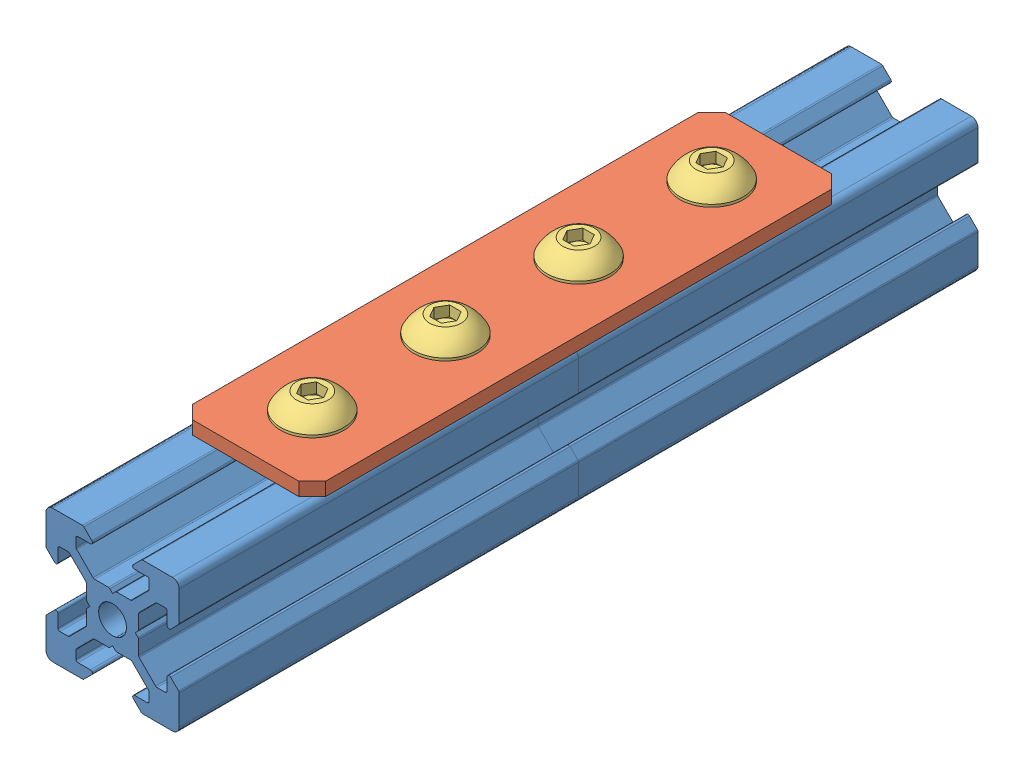
SolidWorks assembly П-Пластина 20 серия 1х4 4отв 20х80х2 СБ, configuration По умолчанию. Lengths in mm.
Overall size (20 24.75 120).
7 component instances, 3 part files, 14 mates.
Components (placement in the parent):
- 2020100-1: 2020100 [По умолчанию] at origin size (20 20 60)
- 2020100-2: 2020100 [По умолчанию] at (0 0 -60) size (20 20 60)
- П-Пластина 20 серия 1х4 4отв 20х80х2-1: П-Пластина 20 серия 1х4 4отв 20х80х2 [По умолчанию] at (0 12 0) x (1 0 0) z (0 -1 0) size (20 80 2)
- socket button head screw_iso-1: socket button head screw_iso [ISO 7380 - M5 x 10 - 10N] at (0 14.75 10) x (0 -1 0) z (0 0 1) size (12.75 9.5 9.5)
- socket button head screw_iso-2: socket button head screw_iso [ISO 7380 - M5 x 10 - 10N] at (0 14.75 -10) x (0 -1 0) z (0 0 1) size (12.75 9.5 9.5)
- socket button head screw_iso-3: socket button head screw_iso [ISO 7380 - M5 x 10 - 10N] at (0 14.75 -30) x (0 -1 0) z (0 0 1) size (12.75 9.5 9.5)
- socket button head screw_iso-4: socket button head screw_iso [ISO 7380 - M5 x 10 - 10N] at (0 14.75 30) x (0 -1 0) z (0 0 1) size (12.75 9.5 9.5)
Mates (geometry in assembly coordinates):
- Совпадение1: coincident anti-aligned: plane of 2020100-1 through (0 0 0) normal (0 0 -1); plane of 2020100-2 through (0 0 0) normal (0 0 1)
- Совпадение2: coincident aligned: plane of 2020100-1 through (-10 10 60) normal (0 1 0); plane of 2020100-2 through (-10 10 0) normal (0 1 0)
- Совпадение3: coincident aligned: plane of 2020100-1 through (10 10 60) normal (1 0 0); plane of 2020100-2 through (10 10 0) normal (1 0 0)
- Совпадение4: coincident anti-aligned: plane of 2020100-1 through (-10 10 60) normal (0 1 0); plane of П-Пластина 20 серия 1х4 4отв 20х80х2-1 through (0 10 0) normal (0 -1 0)
- Совпадение5: coincident aligned: plane of 2020100-1 through (10 10 60) normal (1 0 0); plane of П-Пластина 20 серия 1х4 4отв 20х80х2-1 through (10 10 -40) normal (1 0 0)
- Расстояние1: distance = 20 mm aligned: plane of П-Пластина 20 серия 1х4 4отв 20х80х2-1 through (-10 10 40) normal (0 0 1); plane of 2020100-1 through (0 0 60) normal (0 0 1)
- Концентричный1: concentric anti-aligned: cylinder of П-Пластина 20 серия 1х4 4отв 20х80х2-1 through (0 10 10) axis (0 -1 0) radius 2.75; cylinder of socket button head screw_iso-1 through (0 14.75 10) axis (0 1 0) radius 4.75
- Совпадение7: coincident anti-aligned: plane of П-Пластина 20 серия 1х4 4отв 20х80х2-1 through (0 12 0) normal (0 1 0); plane of socket button head screw_iso-1 through (2.5 12 10) normal (0 -1 0)
- Концентричный2: concentric anti-aligned: cylinder of П-Пластина 20 серия 1х4 4отв 20х80х2-1 through (0 10 -10) axis (0 -1 0) radius 2.75; cylinder of socket button head screw_iso-2 through (0 14.75 -10) axis (0 1 0) radius 4.75
- Совпадение8: coincident anti-aligned: plane of П-Пластина 20 серия 1х4 4отв 20х80х2-1 through (0 12 0) normal (0 1 0); plane of socket button head screw_iso-2 through (2.5 12 -10) normal (0 -1 0)
- Концентричный3: concentric anti-aligned: cylinder of П-Пластина 20 серия 1х4 4отв 20х80х2-1 through (0 10 -30) axis (0 -1 0) radius 2.75; cylinder of socket button head screw_iso-3 through (0 14.75 -30) axis (0 1 0) radius 4.75
- Совпадение9: coincident anti-aligned: plane of П-Пластина 20 серия 1х4 4отв 20х80х2-1 through (0 12 0) normal (0 1 0); plane of socket button head screw_iso-3 through (2.5 12 -30) normal (0 -1 0)
- Концентричный4: concentric anti-aligned: cylinder of П-Пластина 20 серия 1х4 4отв 20х80х2-1 through (0 10 30) axis (0 -1 0) radius 2.75; cylinder of socket button head screw_iso-4 through (0 14.75 30) axis (0 1 0) radius 4.75
- Совпадение10: coincident anti-aligned: plane of П-Пластина 20 серия 1х4 4отв 20х80х2-1 through (0 12 0) normal (0 1 0); plane of socket button head screw_iso-4 through (2.5 12 30) normal (0 -1 0)
